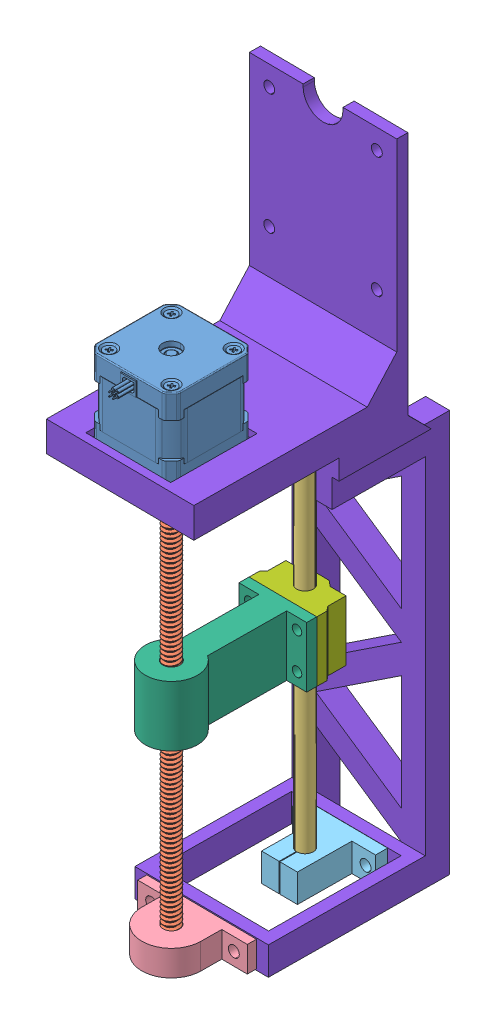
SolidWorks assembly replica-v002, configuration Default. Lengths in mm.
Overall size (75.13 339.91 134.82).
9 component instances, 8 part files, 25 mates.
Components (placement in the parent):
- Nema17-1: Nema17 [Default] at (-46.7057 64.8353 -4.5862) x (-1 0 0) z (0 0 1) size (42.3 62.01 51.35)
- threaded-rod-1: threaded-rod [Default] at (-46.7057 -3.1568 -4.5862) x (0.952048 0 -0.30595) z (0 -1 0) size (8.28 9.24 200.12)
- smooth-rod-1: smooth-rod [Default] at (-46.1306 2.1481 -70.4837) x (0.999962 0 0.008727) z (0 -1 0) size (8 8 200)
- threaded-rod-holder-1: threaded-rod-holder [Default] at (-46.5757 -183.2647 -19.4857) x (0.999962 0 0.008727) z (0 -1 0) size (55 29.61 12.8)
- smooth-rod-holder-1: smooth-rod-holder [Default] at (-45.9535 -182.6647 -90.7829) x (0.999962 0 0.008727) z (0 -1 0) size (41.7 32.9 14)
- smooth-rod-holder-2: smooth-rod-holder [Default] at (-45.9535 3.3353 -90.7829) x (0.999962 0 0.008727) z (0 -1 0) size (41.7 32.9 14)
- cartridge-v001-1: cartridge-v001 [Default] at (-46.2258 -99.4881 -59.5841) x (-0.008727 0 0.999962) z (-0.999962 0 -0.008727) size (68 30 34)
- linear-bearing-1: linear-bearing [Default] at (-46.2258 -99.4881 -59.5841) x (0.999962 0 0.008727) z (0 1 0) size (34 18.67 30)
- full-toolhead-v001-1: full-toolhead-v001 [Default] at (-46.238 -196.6647 -58.1842) x (-0.008727 0 0.999962) z (-0.999962 0 -0.008727) size (129.6 333.37 74)
Mates (geometry in assembly coordinates):
- Coincident1: coincident anti-aligned: plane of Nema17-1 through (-46.7057 24.8353 -4.5862) normal (0 -1 0); plane of motor-bracket-v001-1 through (0.5566 27.6652 -30.8609) normal (0.008727 0.999962 0)
- Concentric1: concentric aligned: cylinder of Nema17-1 through (-46.7057 2.8353 -4.5862) axis (0 1 0) radius 2.5; cylinder of motor-bracket-v001-1 through (-46.042 16.5714 -5.5609) axis (0.008727 0.999962 0) radius 11.5
- Parallel1: parallel anti-aligned: plane of Nema17-1 through (-46.7057 24.8353 16.4138) normal (0 0 1); plane of motor-bracket-v001-1 through (-67.1909 28.2564 15.7391) normal (0 0 -1)
- Concentric3: concentric aligned: cylinder of threaded-rod-1 through (-46.7057 -203.1568 -4.5862) axis (0 1 0) radius 4; cylinder of threaded-rod-holder-1 through (-46.7057 -196.0647 -4.5862) axis (0 1 0) radius 4.1
- Concentric4: concentric aligned: cylinder of smooth-rod-1 through (-46.1306 -197.8519 -70.4837) axis (0 1 0) radius 4; cylinder of smooth-rod-holder-1 through (-46.1306 -196.6647 -70.4837) axis (0 1 0) radius 4.15
- Concentric5: concentric aligned: cylinder of smooth-rod-1 through (-46.1306 -197.8519 -70.4837) axis (0 1 0) radius 4; cylinder of smooth-rod-holder-2 through (-46.1306 -10.6647 -70.4837) axis (0 1 0) radius 4.15
- Concentric6: concentric anti-aligned: cylinder of threaded-rod-1 through (-46.7057 -203.1568 -4.5862) axis (0 1 0) radius 4; cylinder of cartridge-v001-1 through (-46.7057 -69.4881 -4.5862) axis (0 -1 0) radius 4.25
- Coincident4: coincident anti-aligned: line of cartridge-v001-1 through (-29.2264 -69.4881 -59.4358) axis (-0.999962 0 -0.008727); line of linear-bearing-1 through (-63.2251 -69.4881 -59.7325) axis (0.999962 0 0.008727)
- Coincident5: coincident aligned: line of cartridge-v001-1 through (-63.2251 -69.4881 -59.7325) axis (0 -1 0); line of linear-bearing-1 through (-63.2251 -69.4881 -59.7325) axis (0 -1 0)
- Concentric7: concentric anti-aligned: cylinder of smooth-rod-1 through (-46.1306 -197.8519 -70.4837) axis (0 1 0) radius 4; cylinder of linear-bearing-1 through (-46.1306 -69.4881 -70.4837) axis (0 -1 0) radius 4.1
- Coincident6: coincident anti-aligned: plane of threaded-rod-holder-1 through (-46.5757 -196.0647 -19.4857) normal (0.008727 0 -0.999962); plane of bottom-rectangle-v001-1 through (-46.0749 -182.4641 -19.1393) normal (0.000688 0.008727 0.999962)
- Parallel2: parallel anti-aligned: plane of smooth-rod-holder-1 through (-45.9535 -196.6647 -90.7829) normal (0.008727 0 -0.999962); plane of bottom-rectangle-v001-1 through (-46.124 -183.0872 -90.5365) normal (0.000688 0.008727 0.999962)
- Concentric8: concentric anti-aligned: cylinder of smooth-rod-holder-1 through (-30.3912 -189.6647 -57.7459) axis (0.008727 0 -0.999962) radius 2.75; cylinder of bottom-rectangle-v001-1 through (-30.2835 -190.2072 -104.264) axis (0.000688 0.008727 0.999962) radius 2.75
- Concentric9: concentric anti-aligned: cylinder of threaded-rod-holder-1 through (-26.0849 -189.6647 10.3035) axis (0.008727 0 -0.999962) radius 2.75; cylinder of bottom-rectangle-v001-1 through (-25.3344 -189.5842 -32.8701) axis (0.000688 0.008727 0.999962) radius 2.75
- Parallel3: parallel aligned: plane of threaded-rod-holder-1 through (-46.5757 -183.2647 -19.4857) normal (0 1 0); plane of bottom-rectangle-v001-1 through (-46.1015 -182.8018 -57.8378) normal (0 0.999962 -0.008727)
- Coincident7: coincident anti-aligned: plane of Nema17-1 through (-46.7057 24.8353 -4.5862) normal (0 -1 0); plane of full-toolhead-v001-1 through (-46.238 24.8353 -58.1842) normal (0 1 0)
- Concentric10: concentric aligned: cylinder of Nema17-1 through (-46.7057 2.8353 -4.5862) axis (0 1 0) radius 2.5; cylinder of full-toolhead-v001-1 through (-46.7057 -19.1916 -4.5862) axis (0 1 0) radius 11.5
- Concentric11: concentric aligned: cylinder of Nema17-1 through (-46.7057 2.8353 -4.5862) axis (0 1 0) radius 2.5; cylinder of threaded-rod-1 through (-46.7057 -203.1568 -4.5862) axis (0 1 0) radius 4
- Parallel4: parallel anti-aligned: plane of smooth-rod-holder-1 through (-45.9535 -196.6647 -90.7829) normal (0.008727 0 -0.999962); plane of full-toolhead-v001-1 through (-45.9526 -182.6647 -90.8829) normal (-0.008727 0 0.999962)
- Parallel5: parallel anti-aligned: plane of smooth-rod-holder-2 through (-45.9535 -10.6647 -90.7829) normal (0.008727 0 -0.999962); plane of full-toolhead-v001-1 through (-12.4539 -10.6647 -90.5906) normal (-0.008727 0 0.999962)
- Coincident10: coincident anti-aligned: plane of smooth-rod-holder-2 through (-45.9535 3.3353 -90.7829) normal (0 1 0); plane of full-toolhead-v001-1 through (52.3828 3.3353 -57.3235) normal (0 -1 0)
- Concentric12: concentric anti-aligned: cylinder of smooth-rod-holder-2 through (-62.09 -3.6647 -58.0225) axis (0.008727 0 -0.999962) radius 2.75; cylinder of full-toolhead-v001-1 through (-61.6449 -3.6647 -109.0206) axis (-0.008727 0 0.999962) radius 2.75
- Concentric13: concentric anti-aligned: cylinder of smooth-rod-holder-1 through (-62.09 -189.6647 -58.0225) axis (0.008727 0 -0.999962) radius 2.75; cylinder of full-toolhead-v001-1 through (-61.6818 -189.6647 -104.7989) axis (-0.008727 0 0.999962) radius 2.75
- Coincident11: coincident anti-aligned: plane of threaded-rod-holder-1 through (-46.5757 -196.0647 -19.4857) normal (0.008727 0 -0.999962); plane of full-toolhead-v001-1 through (-46.5757 -182.6647 -19.4857) normal (-0.008727 0 0.999962)
- Concentric14: concentric anti-aligned: cylinder of threaded-rod-holder-1 through (-67.5833 -189.6647 9.9414) axis (0.008727 0 -0.999962) radius 2.75; cylinder of full-toolhead-v001-1 through (-67.2047 -189.6647 -33.4444) axis (-0.008727 0 0.999962) radius 2.75
